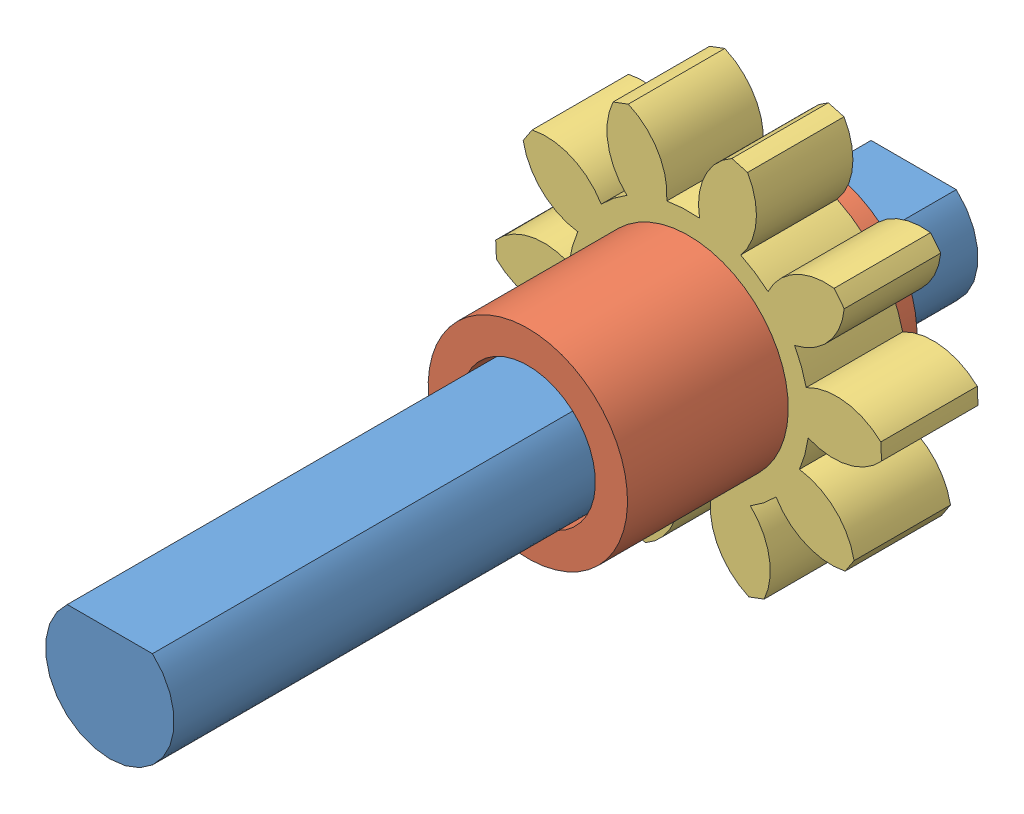
SolidWorks assembly inputshaft, configuration Default. Lengths in mm.
Overall size (12.52 12.1 25).
4 component instances, 3 part files, 7 mates.
Components (placement in the parent):
- axel-1: axel [25mm] at (8.6868 17.7051 16.365) size (4 3.5 25)
- spacer-1: spacer [1mm] at (8.6868 17.7051 19.365) size (6.2 6.2 1)
- spacer-2: spacer [5mm ] at (8.6868 17.7051 23.365) x (-0.097473 -0.995238 0) z (0 0 1) size (6.2 6.2 5)
- Root_gear-1: Root_gear [10T 1.0Mod] at (8.6868 17.7051 20.365) x (0.998946 0.045893 0) z (0 0 1) size (12 11.56 3)
Mates (geometry in assembly coordinates):
- Concentric1: concentric anti-aligned: cylinder of axel-1 through (8.6868 17.7051 41.365) axis (0 0 -1) radius 2; cylinder of Root_gear-1 through (8.6868 17.7051 20.365) axis (0 0 1) radius 2
- Concentric2: concentric aligned: cylinder of axel-1 through (8.6868 17.7051 41.365) axis (0 0 -1) radius 2; cylinder of spacer-1 through (8.6868 17.7051 20.365) axis (0 0 -1) radius 2.1
- Coincident2: coincident anti-aligned: plane of spacer-1 through (8.6868 17.7051 20.365) normal (0 0 1); plane of Root_gear-1 through (8.6868 17.7051 20.365) normal (0 0 -1)
- Concentric3: concentric aligned: cylinder of axel-1 through (8.6868 17.7051 41.365) axis (0 0 -1) radius 2; cylinder of spacer-2 through (8.6868 17.7051 28.365) axis (0 0 -1) radius 2.1
- Coincident3: coincident anti-aligned: plane of spacer-2 through (8.6868 17.7051 23.365) normal (0 0 -1); plane of Root_gear-1 through (8.6868 17.7051 23.365) normal (0 0 1)
- Parallel1: parallel aligned: line of axel-1 through (10.0118 19.2032 41.365) axis (-1 0 0); line of Root_gear-1 through (10.0096 19.2051 23.365) axis (-1 0 0)
- Distance1: distance = 3 mm aligned: plane of spacer-1 through (8.6868 17.7051 19.365) normal (0 0 -1); plane of axel-1 through (8.6868 17.7051 16.365) normal (0 0 -1)
